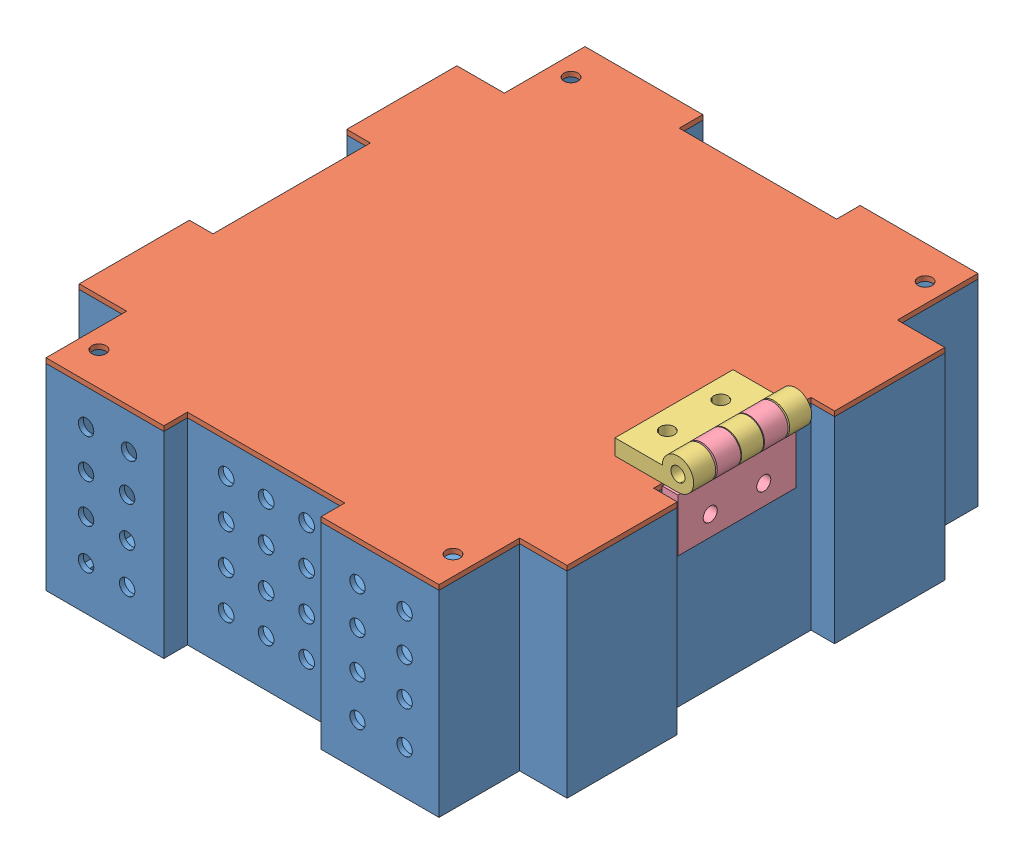
SolidWorks assembly boxwlid_assembly, configuration Default. Lengths in mm.
Overall size (160.02 76.83 173.99).
4 component instances, 4 part files, 5 mates.
Components (placement in the parent):
- foodbox1_v2-1: foodbox1_v2 [Default] at (57.1316 32.5583 142.889) size (157.48 65.09 173.99)
- box_lid-1: box_lid [Default] at (57.1316 96.0583 142.889) size (157.48 1.59 173.99)
- New Hinge Female-2: New Hinge Female [Default] at (113.0116 97.6458 127.4119) size (25.4 10.16 38.1)
- New hinge Male-2: New hinge Male [Default] at (128.2516 79.8658 165.5119) x (0 1 0) z (0 0 -1) size (27.94 10.16 38.1)
Mates (geometry in assembly coordinates):
- Coincident1: coincident aligned: line of foodbox1_v2-1 through (-6.2158 96.0583 229.884) axis (1 0 0); line of box_lid-1 through (-6.2158 96.0583 229.884) axis (1 0 0)
- Coincident2: coincident aligned: line of foodbox1_v2-1 through (31.8156 96.0583 229.884) axis (0 0 -1); line of box_lid-1 through (31.8156 96.0583 229.884) axis (0 0 -1)
- Coincident9: coincident anti-aligned: plane of box_lid-1 through (57.2156 97.6458 142.889) normal (0 1 0); plane of New Hinge Female-2 through (113.0116 97.6458 165.5119) normal (0 -1 0)
- Coincident10: coincident anti-aligned: plane of foodbox1_v2-1 through (128.3356 34.1458 117.489) normal (1 0 0); plane of New hinge Male-2 through (128.3245 80.3859 127.4119) normal (-1 0 0)
- Concentric1: concentric anti-aligned: circle of New Hinge Female-2; circle of New hinge Male-2
